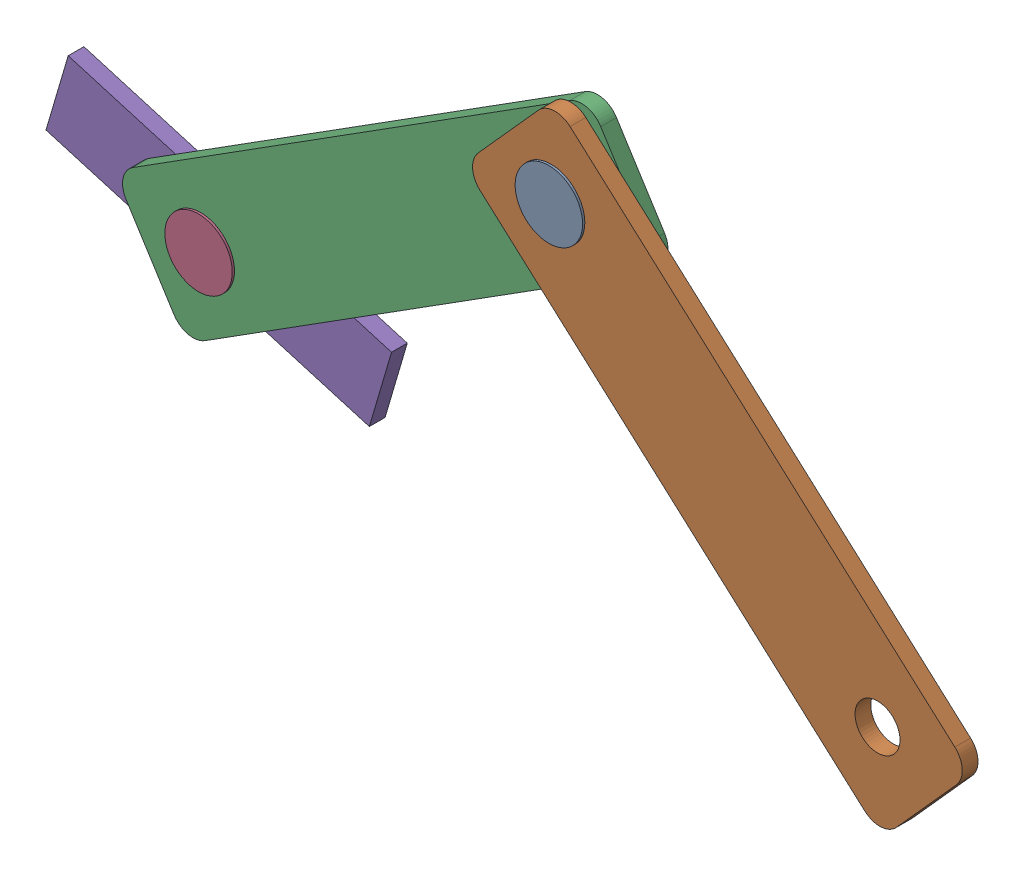
SolidWorks assembly hand_assembly, configuration Default. Lengths in mm.
Overall size (169.52 106.02 13.6).
5 component instances, 3 part files, 8 mates.
Components (placement in the parent):
- bolt-1: bolt [Default] at (5.9881 15.4314 12.9624) size (12 12 6.8)
- link-1: link [Default] at (108.5866 -116.4844 18.5624) size (87.17 81.34 2.8)
- link-2: link [Default] at (95.2816 36.412 15.3624) x (0.272191 0.962243 0) z (0 0 1) size (87.17 81.34 2.8)
- bolt-2: bolt [Default] at (-59.5799 -26.4066 9.7624) x (0.999971 0.007583 0) z (0 0 1) size (12 12 6.8)
- holder-1: holder [Default] at (-59.5799 -26.4066 12.5875) x (-0.959343 0.282242 0) z (0 0 1) size (60 14 6.8)
Mates (geometry in assembly coordinates):
- Concentric2: concentric anti-aligned: cylinder of bolt-1 through (5.9881 15.4314 23.8624) axis (0 0 -1) radius 4; cylinder of link-1 through (5.9881 15.4314 20.6624) axis (0 0 1) radius 4
- Coincident2: coincident anti-aligned: plane of bolt-1 through (5.9881 15.4314 23.4624) normal (0 0 -1); plane of link-1 through (64.8048 -53.0297 23.4624) normal (0 0 1)
- Concentric3: concentric anti-aligned: cylinder of bolt-1 through (5.9881 15.4314 23.8624) axis (0 0 -1) radius 4; cylinder of link-2 through (5.9881 15.4314 17.4624) axis (0 0 1) radius 4
- Coincident3: coincident anti-aligned: circle of bolt-1; plane of link-2 through (22.3057 11.555 17.4624) normal (0 0 -1)
- Concentric4: concentric anti-aligned: cylinder of link-2 through (-59.5799 -26.4066 17.4624) axis (0 0 1) radius 4; cylinder of bolt-2 through (-59.5799 -26.4066 20.6624) axis (0 0 -1) radius 4
- Coincident4: coincident anti-aligned: plane of link-2 through (22.3057 11.555 20.2624) normal (0 0 1); plane of bolt-2 through (-59.5799 -26.4066 20.2624) normal (0 0 -1)
- Coincident5: coincident anti-aligned: cylinder of bolt-2 through (-59.5799 -26.4066 20.6624) axis (0 0 -1) radius 4; circle of holder-1
- Coincident6: coincident anti-aligned: plane of bolt-2 through (-59.5799 -26.4066 14.2624) normal (0 0 1); plane of holder-1 through (-59.5799 -26.4066 14.2624) normal (0 0 -1)
